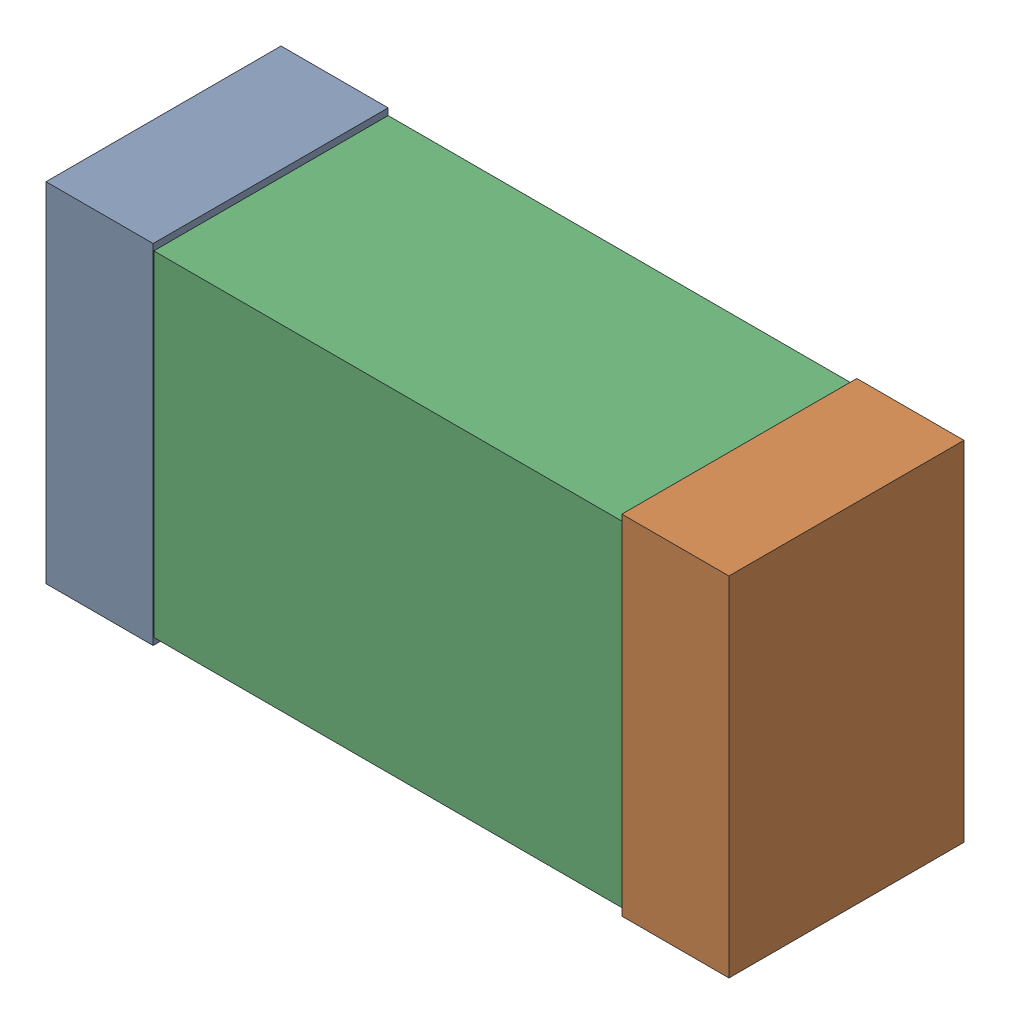
SolidWorks assembly C41, configuration Default. Lengths in mm.
Overall size (1.02 0.52 0.35).
6 component instances, 2 part files, 0 mates.
Components (placement in the parent):
- 870940480-1: 870940480 [Default] at (68.835 44.143 0) size (0.16 0.52 0.35)
  - Extruded-1: Extruded [Default] at origin size (0.16 0.52 0.35)
- 870940480-2: 870940480 [Default] at (69.695 44.143 0) size (0.16 0.52 0.35)
  - Extruded-1: Extruded [Default] at origin size (0.16 0.52 0.35)
- 870940640-1: 870940640 [Default] at (69.265 44.143 0) size (1 0.5 0.35)
  - Extruded_2-1: Extruded_2 [Default] at origin size (1 0.5 0.35)
